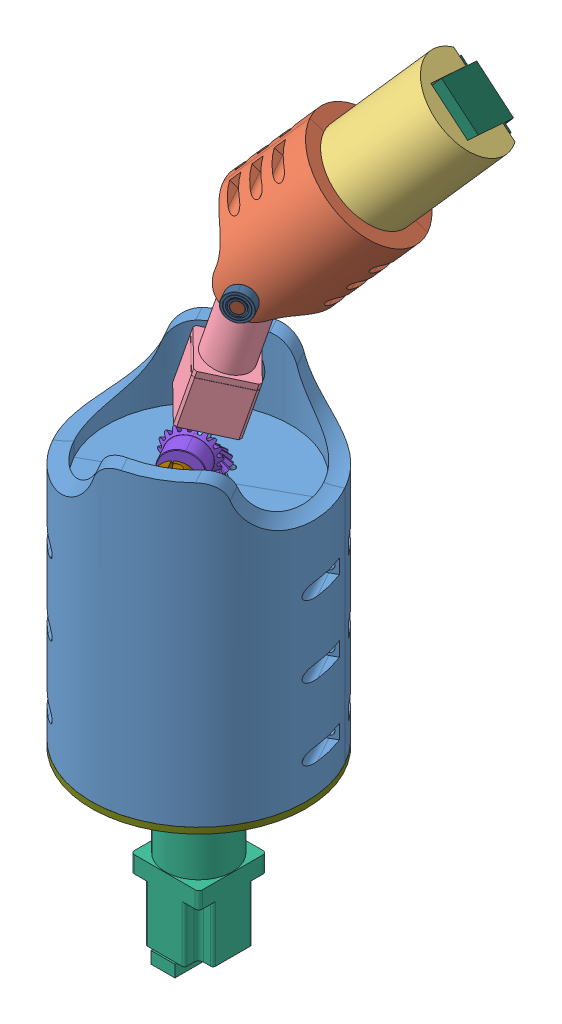
SolidWorks assembly robot_assembly, configuration Default. Lengths in mm.
Overall size (320.62 694.44 254.34).
32 component instances, 21 part files, 58 mates.
Components (placement in the parent):
- base-1: base [Default] at (-126.3481 20.4819 255.3609) x (1 0 0) z (0 -1 0) size (200 200 240) (hidden)
- pin-1: pin [Default] at (-274.4396 150.4819 286.0136) x (0.245906 -0.969294 0) z (-0.969294 -0.245906 0)
- link1-1: link1 [Default] at (-276.3481 25.4819 367.8609) x (0.874496 0 -0.485032) z (0.485032 0 0.874496) size (180 250 180)
- link2-1: link2 [Default] at (-229.6665 413.4466 350.7529) x (-0.83934 0.28069 0.465533) z (0.485032 0 0.874496) size (130 200 130) (hidden)
- pin-2: pin [Default] at (-423.5923 -37.5432 280.9935) x (0.92512 -0.379676 0) z (-0.379676 -0.92512 0)
- link3-1: link3 [Default] at (-243.4829 383.3637 358.6906) x (-0.634707 0.687909 0.352035) z (-0.485032 0 -0.874496) size (100 107.37 100)
- link4-1: link4 [Default] at (-185.2355 453.639 326.3841) x (-0.207024 -0.261764 -0.942667) z (0.771524 -0.636159 0.007213) size (86.2 110 86.2)
- tool-1: tool [Default] at (-244.104 596.3425 266.5799) x (-0.59102 -0.734386 0.333725) z (0.779638 -0.626224 0.002672) size (112.25 10 155.78) (hidden)
- motor_nema17_planetary-1: motor_nema17_planetary [Default] at (-253.9862 317.6956 394.5204) x (0.712498 -0.083393 0.696701) z (0.657339 -0.268016 -0.704324) size (42.32 119.7 42.32)
- shafts-1: shafts [100mm] at (-239.0006 245.4819 435.1971) x (-0.773999 0.46544 0.429292) z (-0.407026 -0.885079 0.225753) size (12.7 165 12.7)
- pin-3: pin [Default] at (-636.3952 170.9653 731.3736) x (0 -0.969294 -0.245906) z (0 -0.245906 0.969294)
- motor_nema23_planetary-2: motor_nema23_planetary [Default] at (-304.8481 -61.5181 339.3609) x (-1 0 0) z (0 -1 0) size (57 58.5 168)
- motor_nema23_planetary-3: motor_nema23_planetary [Default] at (-315.0946 133.3153 356.7611) x (-0.874496 0 0.485032) z (0 -1 0) size (57 58.5 168)
- bearing_05in_id-1: bearing_05in_id [Default] at (-311.9634 245.4819 303.6477) x (0.797029 -0.411489 -0.442065) z (0.485032 0 0.874496) size (22.23 22.23 7.14)
- bearing_05in_id-2: bearing_05in_id [Default] at (-240.7328 245.4819 432.074) x (0.784409 -0.442063 -0.435066) z (0.485032 0 0.874496) size (22.23 22.23 7.14)
- bevel_gear_58-1: bevel_gear_58 [Default] at (-276.3481 226.4319 367.8609) x (0.485032 0 0.874496) z (-0.874496 0 0.485032) size (58.69 58.83 41.54)
- bearing_05in_id-4: bearing_05in_id [Default] at (-298.6062 245.4819 327.7302) x (0.797029 -0.411489 -0.442065) z (0.485032 0 0.874496) size (22.23 22.23 7.14)
- bearing_05in_id-5: bearing_05in_id [Default] at (-246.6387 245.4819 421.4259) x (0.797029 -0.411489 -0.442065) z (0.485032 0 0.874496) size (22.23 22.23 7.14)
- collar_05in_bore-1: collar_05in_bore [Default] at (-296.874 245.4819 330.8533) x (-0.849595 -0.236936 0.471221) z (-0.2072 0.971525 0.114921) size (28.57 10.32 28.57)
- collar_05in_bore-2: collar_05in_bore [Default] at (-253.3758 245.4819 409.2792) x (-0.850922 -0.230625 0.471957) z (-0.201681 0.973043 0.111861) size (28.57 10.32 28.57)
- bearing_38in_bore-1: bearing_38in_bore [Default] at (-262.2227 394.2506 303.6293) x (-0.874496 0 0.485032) z (-0.485032 0 -0.874496) size (22.23 22.23 8.73)
- shaft2-1: shaft2 [Default] at (-204.811 394.2506 407.1406) x (-0.726168 -0.557191 0.402763) z (-0.485032 0 -0.874496) size (9.53 9.53 120)
- bearing_38in_bore-2: bearing_38in_bore [Default] at (-206.9288 394.2506 403.3223) x (-0.874496 0 0.485032) z (-0.485032 0 -0.874496) size (22.23 22.23 8.73)
- belev_gear_38-2: belev_gear_38 [Default] at (-226.4909 394.2506 368.0526) x (-0.245463 -0.959798 0.136144) z (0.83934 -0.28069 -0.465533) size (51.13 51.3 35.92)
- bearing_38in_bore-3: bearing_38in_bore [Default] at (-214.0879 394.2506 390.4148) x (-0.359447 0.91162 0.199364) z (-0.485032 0 -0.874496) size (22.23 22.23 8.73)
- bearing_38in_bore-4: bearing_38in_bore [Default] at (-254.8308 394.2506 316.9566) x (-0.359447 0.91162 0.199364) z (-0.485032 0 -0.874496) size (22.23 22.23 8.73)
- thrust_bearing_3in-1: thrust_bearing_3in [Default] at (-184.2805 454.7912 325.8545) x (-0.601574 -0.725797 0.333658) z (-0.765383 0.643284 0.019359) size (3.2 92.08 92.08)
- collar_05in_bore-3: collar_05in_bore [Default] at (-252.713 394.2506 320.7749) x (-0.849595 -0.236936 0.471221) z (-0.2072 0.971525 0.114921) size (28.57 10.32 28.57)
- simple_stepper-1: simple_stepper [Default] at (-207.6594 431.2664 329.6732) x (-0.634696 0.687909 0.352054) z (-0.485046 0.000015 -0.874489) size (42 30.5 31)
- servo_sf3218MG-1: servo_sf3218MG [Default] at (-139.2684 540.8475 301.5393) x (-0.207024 -0.261764 -0.942667) z (0.771524 -0.636159 0.007213) size (45.72 18.8 54.86)
- thrust_bearing_180mm_OD-1: thrust_bearing_180mm_OD [Default] at (-276.3481 20.4819 367.8609) x (0.73559 0 0.677427) z (-0.677427 0 0.73559) size (180 5 180)
- boushing916-1: boushing916 [Default] at (-276.3481 45.8819 367.8609) x (0 -1 0) z (0.862665 0 0.505777) size (25.75 50.8 50.8)
Mates (geometry in assembly coordinates):
- Tangent3: tangent aligned: cylinder of link1-1 through (-276.3481 275.4819 367.8609) axis (0 -1 0) radius 77; plane of shafts-1 through (-239.0006 245.4819 435.1971) normal (0.485032 0 0.874496)
- Concentric19: concentric aligned: cylinder of base-1 through (-276.3481 20.4819 367.8609) axis (0 -1 0) radius 6.5; cylinder of motor_nema23_planetary-2 through (-276.3481 38.4819 367.8609) axis (0 -1 0) radius 6
- Concentric20: concentric anti-aligned: circle of base-1; circle of motor_nema23_planetary-2
- Coincident5: coincident anti-aligned: plane of base-1 through (-126.3481 10.4819 480.3609) normal (0 -1 0); plane of motor_nema23_planetary-2 through (-276.3481 10.4819 367.8609) normal (0 1 0)
- Concentric22: concentric aligned: cylinder of link1-1 through (-308.8452 245.4819 309.2696) axis (-0.485032 0 -0.874496) radius 14.2875; cylinder of bearing_05in_id-1 through (-310.058 245.4819 307.083) axis (-0.485032 0 -0.874496) radius 11.1125
- Tangent4: tangent aligned: cylinder of link1-1 through (-276.3481 275.4819 367.8609) axis (0 -1 0) radius 77; plane of bearing_05in_id-1 through (-313.6955 245.4819 300.5246) normal (-0.485032 0 -0.874496)
- Concentric23: concentric anti-aligned: cylinder of shafts-1 through (-319.0309 245.4819 290.9052) axis (0.485032 0 0.874496) radius 6.35; cylinder of bearing_05in_id-1 through (-310.058 245.4819 307.083) axis (-0.485032 0 -0.874496) radius 4.7625
- Concentric24: concentric aligned: circle of link1-1; cylinder of bearing_05in_id-2 through (-238.8274 245.4819 435.5094) axis (-0.485032 0 -0.874496) radius 11.1125
- Tangent6: tangent aligned: cylinder of link1-1 through (-276.3481 275.4819 367.8609) axis (0 -1 0) radius 77; plane of bearing_05in_id-2 through (-239.0006 245.4819 435.1971) normal (0.485032 0 0.874496)
- Concentric30: concentric anti-aligned: cylinder of shafts-1 through (-319.0309 245.4819 290.9052) axis (0.485032 0 0.874496) radius 6.35; cylinder of bevel_gear_58-1 through (-257.2101 245.4819 402.366) axis (-0.485032 0 -0.874496) radius 6.35
- Concentric31: concentric anti-aligned: cylinder of motor_nema23_planetary-3 through (-276.3481 233.3153 367.8609) axis (0 -1 0) radius 6; cylinder of bevel_gear_58-1 through (-276.3481 206.0247 367.8609) axis (0 1 0) radius 6.35
- Coincident8: coincident aligned: circle of motor_nema23_planetary-3; plane of bevel_gear_58-1 through (-276.3481 233.3153 367.8609) normal (0 1 0)
- Concentric32: concentric aligned: cylinder of link1-1 through (-297.978 215.4819 361.6645) axis (0 1 0) radius 2.75; cylinder of motor_nema23_planetary-3 through (-297.978 205.3153 361.6645) axis (0 1 0) radius 2.75
- Concentric33: concentric anti-aligned: cylinder of link2-1 through (-296.874 245.4819 330.8533) axis (-0.485032 0 -0.874496) radius 14.351; cylinder of shafts-1 through (-319.0309 245.4819 290.9052) axis (0.485032 0 0.874496) radius 6.35
- Coincident9: coincident aligned: plane of link2-1 through (-296.874 245.4819 330.8533) normal (0.485032 0 0.874496); plane of bearing_05in_id-4 through (-296.874 245.4819 330.8533) normal (0.485032 0 0.874496)
- Concentric35: concentric aligned: cylinder of link2-1 through (-296.874 245.4819 330.8533) axis (-0.485032 0 -0.874496) radius 14.351; cylinder of bearing_05in_id-4 through (-296.7008 245.4819 331.1656) axis (-0.485032 0 -0.874496) radius 11.1125
- Coincident10: coincident aligned: plane of link2-1 through (-248.3708 245.4819 418.3029) normal (-0.485032 0 -0.874496); plane of bearing_05in_id-5 through (-248.3708 245.4819 418.3029) normal (-0.485032 0 -0.874496)
- Concentric36: concentric anti-aligned: cylinder of link2-1 through (-248.3708 245.4819 418.3029) axis (0.485032 0 0.874496) radius 14.351; cylinder of bearing_05in_id-5 through (-244.7333 245.4819 424.8613) axis (-0.485032 0 -0.874496) radius 11.1125
- Concentric37: concentric anti-aligned: cylinder of shafts-1 through (-319.0309 245.4819 290.9052) axis (0.485032 0 0.874496) radius 6.35; cylinder of collar_05in_bore-1 through (-291.8691 245.4819 339.877) axis (-0.485032 0 -0.874496) radius 6.35
- Concentric39: concentric aligned: cylinder of shafts-1 through (-319.0309 245.4819 290.9052) axis (0.485032 0 0.874496) radius 6.35; circle of collar_05in_bore-2
- Distance1: distance = 35 mm aligned: plane of link1-1 through (-308.8452 245.4819 309.2696) normal (0.485032 0 0.874496); plane of collar_05in_bore-1 through (-291.8691 245.4819 339.877) normal (0.485032 0 0.874496)
- Coincident12: coincident aligned: plane of link2-1 through (-296.874 245.4819 330.8533) normal (0.485032 0 0.874496); circle of collar_05in_bore-1
- Coincident13: coincident anti-aligned: plane of bearing_05in_id-5 through (-248.3708 245.4819 418.3029) normal (-0.485032 0 -0.874496); plane of collar_05in_bore-2 through (-248.3708 245.4819 418.3029) normal (0.485032 0 0.874496)
- Concentric40: concentric anti-aligned: cylinder of link2-1 through (-260.1049 394.2506 307.4476) axis (-0.485032 0 -0.874496) radius 11.1125; cylinder of bearing_38in_bore-1 through (-264.5522 394.2506 299.4292) axis (0.485032 0 0.874496) radius 11.1125
- Coincident14: coincident aligned: plane of link2-1 through (-260.1049 394.2506 307.4476) normal (0.485032 0 0.874496); plane of bearing_38in_bore-1 through (-260.1049 394.2506 307.4476) normal (0.485032 0 0.874496)
- Concentric41: concentric aligned: cylinder of link2-1 through (-209.0466 394.2506 399.5041) axis (0.485032 0 0.874496) radius 11.1125; cylinder of bearing_38in_bore-2 through (-209.2583 394.2506 399.1222) axis (0.485032 0 0.874496) radius 11.1125
- Coincident15: coincident aligned: plane of link2-1 through (-209.0466 394.2506 399.5041) normal (-0.485032 0 -0.874496); plane of bearing_38in_bore-2 through (-209.0466 394.2506 399.5041) normal (-0.485032 0 -0.874496)
- Concentric42: concentric aligned: cylinder of shaft2-1 through (-263.0148 394.2506 302.201) axis (0.485032 0 0.874496) radius 4.7625; cylinder of bearing_38in_bore-2 through (-209.2583 394.2506 399.1222) axis (0.485032 0 0.874496) radius 4.7625
- Coincident16: coincident aligned: plane of shaft2-1 through (-204.811 394.2506 407.1406) normal (0.485032 0 0.874496); plane of bearing_38in_bore-2 through (-204.811 394.2506 407.1406) normal (0.485032 0 0.874496)
- Concentric44: concentric anti-aligned: cylinder of shaft2-1 through (-263.0148 394.2506 302.201) axis (0.485032 0 0.874496) radius 4.7625; cylinder of belev_gear_38-2 through (-217.839 394.2506 383.6516) axis (-0.485032 0 -0.874496) radius 4.7625
- Concentric45: concentric anti-aligned: cylinder of motor_nema17_planetary-1 through (-239.6396 374.4501 356.2844) axis (-0.245463 -0.959798 0.136144) radius 4; cylinder of belev_gear_38-2 through (-243.0458 361.1314 358.1736) axis (0.245463 0.959798 -0.136144) radius 4.7625
- Distance3: distance = 10 mm aligned: plane of motor_nema17_planetary-1 through (-239.6396 374.4501 356.2844) normal (0.245463 0.959798 -0.136144); plane of belev_gear_38-2 through (-237.185 384.0481 354.923) normal (0.245463 0.959798 -0.136144)
- Concentric46: concentric anti-aligned: cylinder of link2-1 through (-245.6215 351.0597 359.6023) axis (0.245463 0.959798 -0.136144) radius 10; cylinder of belev_gear_38-2 through (-234.1666 395.8505 353.2489) axis (-0.245463 -0.959798 0.136144) radius 13.1445
- Concentric47: concentric anti-aligned: cylinder of link3-1 through (-210.2077 394.2506 397.4105) axis (-0.485032 0 -0.874496) radius 4.7625; cylinder of shaft2-1 through (-263.0148 394.2506 302.201) axis (0.485032 0 0.874496) radius 4.7625
- Concentric48: concentric aligned: cylinder of link3-1 through (-216.2056 394.2506 386.5965) axis (0.485032 0 0.874496) radius 11.1125; cylinder of bearing_38in_bore-3 through (-216.4174 394.2506 386.2147) axis (0.485032 0 0.874496) radius 11.1125
- Coincident17: coincident anti-aligned: cylinder of link3-1 through (-216.2056 394.2506 386.5965) axis (0.485032 0 0.874496) radius 11.1125; circle of bearing_38in_bore-3
- Coincident18: coincident aligned: plane of link3-1 through (-216.2056 394.2506 386.5965) normal (-0.485032 0 -0.874496); plane of bearing_38in_bore-3 through (-216.2056 394.2506 386.5965) normal (-0.485032 0 -0.874496)
- Concentric49: concentric anti-aligned: cylinder of link3-1 through (-252.713 394.2506 320.7749) axis (-0.485032 0 -0.874496) radius 11.1125; cylinder of bearing_38in_bore-4 through (-257.1603 394.2506 312.7565) axis (0.485032 0 0.874496) radius 11.1125
- Coincident19: coincident aligned: plane of link3-1 through (-252.713 394.2506 320.7749) normal (0.485032 0 0.874496); plane of bearing_38in_bore-4 through (-252.713 394.2506 320.7749) normal (0.485032 0 0.874496)
- Concentric50: concentric anti-aligned: cylinder of shaft2-1 through (-263.0148 394.2506 302.201) axis (0.485032 0 0.874496) radius 4.7625; cylinder of collar_05in_bore-3 through (-247.7081 394.2506 329.7986) axis (-0.485032 0 -0.874496) radius 6.35
- Distance4: distance = 15.24 mm anti-aligned: plane of collar_05in_bore-3 through (-252.713 394.2506 320.7749) normal (-0.485032 0 -0.874496); plane of bearing_38in_bore-1 through (-260.1049 394.2506 307.4476) normal (0.485032 0 0.874496)
- Coincident20: coincident anti-aligned: plane of link3-1 through (-252.713 394.2506 320.7749) normal (0.485032 0 0.874496); plane of collar_05in_bore-3 through (-252.713 394.2506 320.7749) normal (-0.485032 0 -0.874496)
- Coincident21: coincident anti-aligned: plane of link3-1 through (-183.3255 455.9434 325.3248) normal (-0.601574 -0.725797 0.333658); plane of thrust_bearing_3in-1 through (-183.3255 455.9434 325.3248) normal (0.601574 0.725797 -0.333658)
- Coincident22: coincident anti-aligned: plane of link4-1 through (-185.2355 453.639 326.3841) normal (0.601574 0.725797 -0.333658); plane of thrust_bearing_3in-1 through (-185.2355 453.639 326.3841) normal (-0.601574 -0.725797 0.333658)
- Concentric53: concentric aligned: cylinder of link3-1 through (-207.3374 457.0955 329.4946) axis (0.601574 0.725797 -0.333658) radius 2.1; cylinder of simple_stepper-1 through (-207.9383 456.3692 329.8283) axis (0.601574 0.725797 -0.333658) radius 2.1
- Concentric54: concentric aligned: cylinder of link3-1 through (-192.3491 445.0564 330.3296) axis (0.601574 0.725797 -0.333658) radius 5; circle of simple_stepper-1
- Coincident23: coincident anti-aligned: plane of link3-1 through (-192.3491 445.0564 330.3296) normal (-0.601574 -0.725797 0.333658); plane of simple_stepper-1 through (-196.2295 445.0565 323.3337) normal (0.601574 0.725797 -0.333658)
- Concentric55: concentric anti-aligned: cylinder of link3-1 through (-183.3255 455.9434 325.3248) axis (-0.601574 -0.725797 0.333658) radius 50; cylinder of link4-1 through (-191.2513 446.381 329.7207) axis (0.601574 0.725797 -0.333658) radius 43.1
- Concentric57: concentric anti-aligned: cylinder of link4-1 through (-105.0882 512.7901 315.8352) axis (-0.207024 -0.261764 -0.942667) radius 3; cylinder of servo_sf3218MG-1 through (-114.0275 501.4871 275.1309) axis (0.207024 0.261764 0.942667) radius 2.5
- Concentric58: concentric anti-aligned: cylinder of link4-1 through (-110.8946 505.7847 319.0557) axis (-0.207024 -0.261764 -0.942667) radius 3; cylinder of servo_sf3218MG-1 through (-119.8339 494.4817 278.3513) axis (0.207024 0.261764 0.942667) radius 2.5
- Coincident33: coincident anti-aligned: plane of link4-1 through (-169.9922 524.4338 284.283) normal (-0.207024 -0.261764 -0.942667); plane of servo_sf3218MG-1 through (-144.8423 533.7998 276.1589) normal (0.207024 0.261764 0.942667)
- Concentric64: concentric anti-aligned: cylinder of tool-1 through (-145.2173 516.9142 266.9188) axis (-0.207024 -0.261764 -0.942667) radius 6.3754; cylinder of servo_sf3218MG-1 through (-146.3741 515.4515 261.6512) axis (0.207024 0.261764 0.942667) radius 3
- Coincident36: coincident anti-aligned: plane of tool-1 through (-244.104 596.3425 266.5799) normal (0.207024 0.261764 0.942667); plane of servo_sf3218MG-1 through (-147.5767 530.3424 263.7082) normal (-0.207024 -0.261764 -0.942667)
- Coincident37: coincident anti-aligned: plane of base-1 through (-126.3481 20.4819 480.3609) normal (0 1 0); plane of thrust_bearing_180mm_OD-1 through (-276.3481 20.4819 367.8609) normal (0 -1 0)
- Concentric67: concentric aligned: cylinder of motor_nema23_planetary-2 through (-276.3481 38.4819 367.8609) axis (0 -1 0) radius 6; cylinder of boushing916-1 through (-276.3481 47.1519 367.8609) axis (0 -1 0) radius 7.9375
- Concentric68: concentric aligned: cylinder of link1-1 through (-276.3481 275.4819 367.8609) axis (0 -1 0) radius 90; cylinder of boushing916-1 through (-276.3481 47.1519 367.8609) axis (0 -1 0) radius 25.4
- Coincident40: coincident anti-aligned: plane of base-1 through (-126.3481 20.4819 480.3609) normal (0 1 0); plane of boushing916-1 through (-276.3481 20.4819 367.8609) normal (0 -1 0)
- Coincident42: coincident anti-aligned: plane of link1-1 through (-276.3481 25.4819 367.8609) normal (0 -1 0); plane of thrust_bearing_180mm_OD-1 through (-276.3481 25.4819 367.8609) normal (0 1 0)
